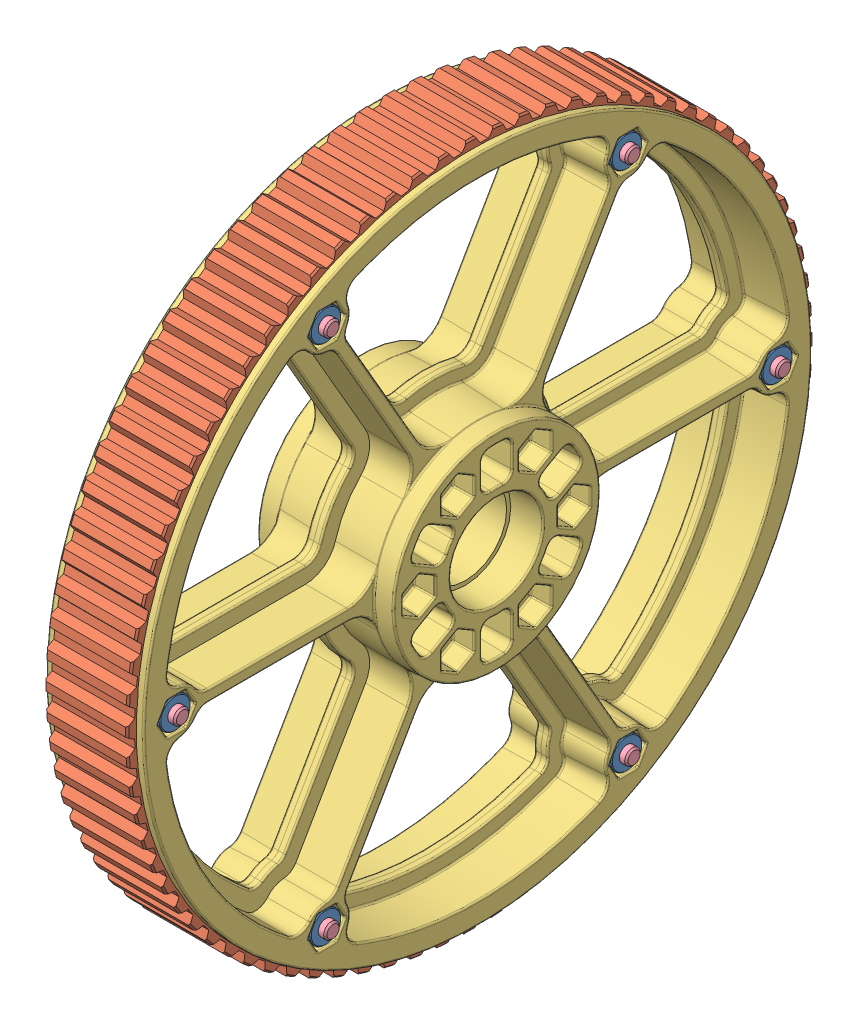
SolidWorks assembly 8PlactionRough, configuration Default. Lengths in mm.
Overall size (41.66 234.45 234.45).
15 component instances, 4 part files, 0 mates.
Components (placement in the parent):
- 10-32_nylock_nut-1: 10-32_nylock_nut [Default] at (125.0283 -70.4661 166.4862) x (0 0.793594 -0.608447) z (-1 0 0) size (11.98 11.69 7.5)
- 10-32_nylock_nut-2: 10-32_nylock_nut [Default] at (125.0283 179.4143 -22.2176) x (0 -0.923728 -0.383049) z (-1 0 0) size (11.98 11.69 7.5)
- 10-32_nylock_nut-3: 10-32_nylock_nut [Default] at (125.0283 70.4661 -166.4862) x (0 -0.793594 0.608447) z (-1 0 0) size (11.98 11.69 7.5)
- 10-32_nylock_nut-4: 10-32_nylock_nut [Default] at (125.0283 -108.9482 -144.2686) x (0 0.130134 0.991496) z (-1 0 0) size (11.98 11.69 7.5)
- 10-32_nylock_nut-5: 10-32_nylock_nut [Default] at (125.0283 -179.4143 22.2176) x (0 0.923728 0.383049) z (-1 0 0) size (11.98 11.69 7.5)
- 10-32_nylock_nut-6: 10-32_nylock_nut [Default] at (125.0283 108.9482 144.2686) x (0 -0.130134 -0.991496) z (-1 0 0) size (11.98 11.69 7.5)
- 8RoughTread-1: 8RoughTread [Default] at (8.128 0 0) x (0 -0.992815 0.119662) z (1 0 0) size (210.74 210.74 25.4)
- 8MW_d01_v2-1: 8MW_d01_v2 [Default] at origin size (22.87 205.23 205.23)
- 8MW_d01_v2-2: 8MW_d01_v2 [Default] at (41.656 0 0) x (-1 0 0) z (0 0 -1) size (22.87 205.23 205.23)
- 10-32x1000_shcs-1: 10-32x1000_shcs [Default] at (7.4168 0 92.456) x (0 -0.961068 -0.276312) z (0 0.276312 -0.961068) size (7.82 30.18 7.82)
- 10-32x1000_shcs-2: 10-32x1000_shcs [Default] at (7.4168 80.0692 -46.228) x (0 0.241241 0.970465) z (0 -0.970465 0.241241) size (7.82 30.18 7.82)
- 10-32x1000_shcs-3: 10-32x1000_shcs [Default] at (7.4168 0 -92.456) x (0 0.961068 0.276312) z (0 -0.276312 0.961068) size (7.82 30.18 7.82)
- 10-32x1000_shcs-4: 10-32x1000_shcs [Default] at (7.4168 -80.0692 -46.228) x (0 0.719827 -0.694154) z (0 0.694154 0.719827) size (7.82 30.18 7.82)
- 10-32x1000_shcs-5: 10-32x1000_shcs [Default] at (7.4168 -80.0692 46.228) x (0 -0.241241 -0.970465) z (0 0.970465 -0.241241) size (7.82 30.18 7.82)
- 10-32x1000_shcs-6: 10-32x1000_shcs [Default] at (7.4168 80.0692 46.228) x (0 -0.719827 0.694154) z (0 -0.694154 -0.719827) size (7.82 30.18 7.82)
